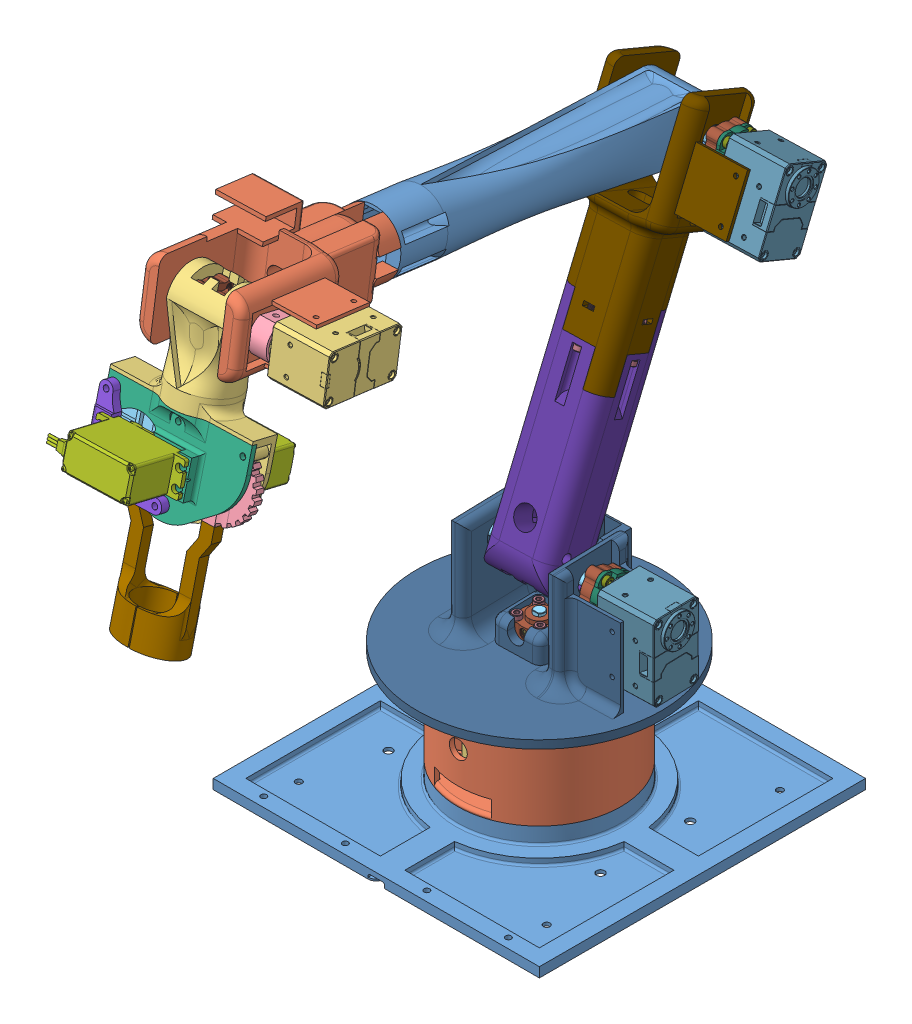
SolidWorks assembly ASSEMBLY_ARM_CHESS_BRAS, configuration Défaut. Lengths in mm.
Overall size (200 394.45 403.36).
100 component instances, 28 part files, 150 mates.
Components (placement in the parent):
- base_robot-1: base_robot [Défaut] at origin size (200 16 200)
- Support_Bearing_V4-1: Support_Bearing_V4 [Défaut] at (0 16 0) x (0 0 1) z (-1 0 0) size (100 58.5 100)
- XL430-W250-1: XL430-W250 [Défaut] at (0 42 0) x (-1 0 0) z (0 1 0) size (28.5 46.5 36.18)
- Coupler_Joint3-1: Coupler_Joint3 [Défaut] at (0 45 0) x (-0.999605 0 0.028091) z (-0.028091 0 -0.999605) size (22.5 11 20.75)
- shaft-1: shaft [2po] at (0 70.4 0) x (0.999605 0 -0.028091) z (0 -1 0) size (6.35 5.71 50.8)
- M3-16mm_91292A115_TYPE 18-8 SS SOCKET HEAD CAP SCREW-1: M3-16mm_91292A115_TYPE 18-8 SS SOCKET HEAD CAP SCREW [91292A115] at (22.5 21 -30) x (0.270289 0 0.962779) z (0 1 0) size (5.5 5.5 19.25)
- M3-16mm_91292A115_TYPE 18-8 SS SOCKET HEAD CAP SCREW-2: M3-16mm_91292A115_TYPE 18-8 SS SOCKET HEAD CAP SCREW [91292A115] at (-22.5 21 30) x (0.142923 0 0.989734) z (0 1 0) size (5.5 5.5 19.25)
- M3-16mm_91292A115_TYPE 18-8 SS SOCKET HEAD CAP SCREW-3: M3-16mm_91292A115_TYPE 18-8 SS SOCKET HEAD CAP SCREW [91292A115] at (-22.5 21 -30) x (-0.967146 0 0.254223) z (0 1 0) size (5.5 5.5 19.25)
- M3-16mm_91292A115_TYPE 18-8 SS SOCKET HEAD CAP SCREW-4: M3-16mm_91292A115_TYPE 18-8 SS SOCKET HEAD CAP SCREW [91292A115] at (22.5 21 30) x (0.348034 0 0.937482) z (0 1 0) size (5.5 5.5 19.25)
- M3-NUT_90710A030_TYPE 18-8 SS THIN HEX NUT - DIN 439B-1: M3-NUT_90710A030_TYPE 18-8 SS THIN HEX NUT - DIN 439B [90710A030] at (22.5 19.4 -30) x (0.887075 0 -0.461625) z (-0.461625 0 -0.887075) size (5.5 2.19 6.35)
- M3-NUT_90710A030_TYPE 18-8 SS THIN HEX NUT - DIN 439B-2: M3-NUT_90710A030_TYPE 18-8 SS THIN HEX NUT - DIN 439B [90710A030] at (-22.5 19.4 -30) x (0.998436 0 0.055912) z (-0.055912 0 0.998436) size (5.5 2.19 6.35)
- M3-NUT_90710A030_TYPE 18-8 SS THIN HEX NUT - DIN 439B-3: M3-NUT_90710A030_TYPE 18-8 SS THIN HEX NUT - DIN 439B [90710A030] at (-22.5 19.4 30) x (0.076416 0 -0.997076) z (0.997076 0 0.076416) size (5.5 2.19 6.35)
- M3-NUT_90710A030_TYPE 18-8 SS THIN HEX NUT - DIN 439B-4: M3-NUT_90710A030_TYPE 18-8 SS THIN HEX NUT - DIN 439B [90710A030] at (22.5 19.4 30) x (-0.208862 0 0.977945) z (-0.977945 0 -0.208862) size (5.5 2.19 6.35)
- bearing-1: bearing [Default] at (0 58.1597 -32.8363) x (0.994869 0.079004 -0.063204) z (0 0.624695 0.780869) size (22.23 22.23 8.73)
- bearing-2: bearing [Default] at (-28.437 58.1597 16.4181) x (0.188165 0.365941 0.911417) z (-0.676252 -0.624695 0.390434) size (22.23 22.23 8.73)
- bearing-3: bearing [Default] at (28.437 58.1597 16.4181) x (0.671098 0.303827 -0.676252) z (0.676252 -0.624695 0.390434) size (22.23 22.23 8.73)
- M2-4mm_TYPE 18-8 SS SOCKET HEAD CAP SCREW-1: M2-4mm_TYPE 18-8 SS SOCKET HEAD CAP SCREW [91292A832] at (-0.2247 43.7 -7.9968) x (0.453166 0 -0.891426) z (0 -1 0) size (3.8 3.8 6.09)
- M2-4mm_TYPE 18-8 SS SOCKET HEAD CAP SCREW-2: M2-4mm_TYPE 18-8 SS SOCKET HEAD CAP SCREW [91292A832] at (-7.9968 43.7 0.2247) x (0.453166 0 -0.891426) z (0 -1 0) size (3.8 3.8 6.09)
- M2-4mm_TYPE 18-8 SS SOCKET HEAD CAP SCREW-3: M2-4mm_TYPE 18-8 SS SOCKET HEAD CAP SCREW [91292A832] at (7.9968 43.7 -0.2247) x (0.453166 0 -0.891426) z (0 -1 0) size (3.8 3.8 6.09)
- base_350W-1: base_350W [Défaut] at (-0.0002 69.5 -0.0002) x (-0.999605 0 0.028091) z (-0.028091 0 -0.999605) size (150 75 150)
- 545548_hub-1: 545548_hub [Default] at (-39.1478 106.1015 -7.8743) x (-0.999605 0 0.028091) z (0.028091 0 0.999605) size (20.57 9.53 20.57)
  - 545548 assembly.STEP-1: 545548 assembly.STEP [Default] at origin size (20.57 9.53 20.57)
    - 545548.STEP-1: 545548.STEP [Default] at (-38.9112 12.0765 8.9709) size (20.57 9.53 20.57)
    - 632138_91375A438.STEP-1: 632138_91375A438.STEP [Default] at (-38.9112 18.109 15.0823) x (0.93363 0.358238 0) z (0 0 1) size (4.83 4.83 6.36)
- M3-20mm_91292A123_TYPE 18-8 SS SOCKET HEAD CAP SCREW-1: M3-20mm_91292A123_TYPE 18-8 SS SOCKET HEAD CAP SCREW [91292A123] at (-6.7178 66.485 7.1063) x (1 0 0) z (0 -1 0) size (5.5 5.5 28.3)
- M3-20mm_91292A123_TYPE 18-8 SS SOCKET HEAD CAP SCREW-2: M3-20mm_91292A123_TYPE 18-8 SS SOCKET HEAD CAP SCREW [91292A123] at (7.1063 66.485 6.7178) x (0.837169 0 0.546944) z (0 -1 0) size (5.5 5.5 28.3)
- M3-20mm_91292A123_TYPE 18-8 SS SOCKET HEAD CAP SCREW-3: M3-20mm_91292A123_TYPE 18-8 SS SOCKET HEAD CAP SCREW [91292A123] at (-7.1063 66.485 -6.7178) x (0.839089 0 0.543994) z (0 -1 0) size (5.5 5.5 28.3)
- M3-20mm_91292A123_TYPE 18-8 SS SOCKET HEAD CAP SCREW-4: M3-20mm_91292A123_TYPE 18-8 SS SOCKET HEAD CAP SCREW [91292A123] at (6.7178 66.485 -7.1063) x (0.837169 0 0.546944) z (0 -1 0) size (5.5 5.5 28.3)
- M3-NUT_90710A030_TYPE 18-8 SS THIN HEX NUT - DIN 439B-5: M3-NUT_90710A030_TYPE 18-8 SS THIN HEX NUT - DIN 439B [90710A030] at (6.7178 73.6 -7.1063) x (-0.877485 0 0.479605) z (0.479605 0 0.877485) size (5.5 2.19 6.35)
- M3-NUT_90710A030_TYPE 18-8 SS THIN HEX NUT - DIN 439B-6: M3-NUT_90710A030_TYPE 18-8 SS THIN HEX NUT - DIN 439B [90710A030] at (-7.1063 73.6 -6.7178) x (0.422721 0 0.90626) z (0.90626 0 -0.422721) size (5.5 2.19 6.35)
- M3-NUT_90710A030_TYPE 18-8 SS THIN HEX NUT - DIN 439B-7: M3-NUT_90710A030_TYPE 18-8 SS THIN HEX NUT - DIN 439B [90710A030] at (-6.7178 73.6 7.1063) x (0.887517 0 0.460775) z (0.460775 0 -0.887517) size (5.5 2.19 6.35)
- M3-NUT_90710A030_TYPE 18-8 SS THIN HEX NUT - DIN 439B-8: M3-NUT_90710A030_TYPE 18-8 SS THIN HEX NUT - DIN 439B [90710A030] at (7.1063 73.6 6.7178) x (0.999903 0 0.013926) z (0.013926 0 -0.999903) size (5.5 2.19 6.35)
- XM430-W350-1: XM430-W350 [Default] at (64.9812 125 -1.5762) x (0.028091 0 0.999605) z (-0.999605 0 0.028091) size (28.5 46.5 42.4)
- coupleur350W-1: coupleur350W [Défaut] at (42.9898 125 -0.9582) x (-0.025922 -0.385253 -0.922447) z (-0.010822 0.922811 -0.385101) size (22.5 5 22.5)
- 545548_hub-2: 545548_hub [Default] at (18.2948 117.7261 -39.5435) x (-0.025765 -0.398399 -0.91685) z (0.011191 -0.917212 0.398242) size (20.57 9.53 20.57)
  - 545548 assembly.STEP-1: 545548 assembly.STEP [Default] at origin size (20.57 9.53 20.57)
    - 545548.STEP-1: 545548.STEP [Default] at (-38.9112 12.0765 8.9709) size (20.57 9.53 20.57)
    - 632138_91375A438.STEP-1: 632138_91375A438.STEP [Default] at (-38.9112 18.109 15.0823) x (0.93363 0.358238 0) z (0 0 1) size (4.83 4.83 6.36)
- M3-8mm_91292A112_TYPE 18-8 SS SOCKET HEAD CAP SCREW-1: M3-8mm_91292A112_TYPE 18-8 SS SOCKET HEAD CAP SCREW [91292A112] at (34.8885 115.9482 -4.4519) x (0.026773 -0.302684 0.952715) z (-0.999605 0 0.028091) size (5.5 5.5 11.2)
- M3-8mm_91292A112_TYPE 18-8 SS SOCKET HEAD CAP SCREW-2: M3-8mm_91292A112_TYPE 18-8 SS SOCKET HEAD CAP SCREW [91292A112] at (35.2473 121.2801 8.3148) x (0.02653 -0.328692 0.944065) z (-0.999605 0 0.028091) size (5.5 5.5 11.2)
- M3-8mm_91292A112_TYPE 18-8 SS SOCKET HEAD CAP SCREW-3: M3-8mm_91292A112_TYPE 18-8 SS SOCKET HEAD CAP SCREW [91292A112] at (34.7387 128.7199 -9.7817) x (0.027877 0.123058 0.992008) z (-0.999605 0 0.028091) size (5.5 5.5 11.2)
- M3-8mm_91292A112_TYPE 18-8 SS SOCKET HEAD CAP SCREW-4: M3-8mm_91292A112_TYPE 18-8 SS SOCKET HEAD CAP SCREW [91292A112] at (35.0975 134.0518 2.985) x (0.026768 -0.303288 0.952523) z (-0.999605 0 0.028091) size (5.5 5.5 11.2)
- shaft-2: shaft [3po] at (3.5054 125 0.1514) x (-0.025765 -0.398399 -0.91685) z (-0.999605 0 0.028091) size (6.35 5.71 76.2)
- 545548_hub-3: 545548_hub [Default] at (-12.9324 117.726 -38.6657) x (-0.025765 -0.398399 -0.91685) z (0.011191 -0.917212 0.398242) size (20.57 9.53 20.57)
  - 545548 assembly.STEP-1: 545548 assembly.STEP [Default] at origin size (20.57 9.53 20.57)
    - 545548.STEP-1: 545548.STEP [Default] at (-38.9112 12.0765 8.9709) size (20.57 9.53 20.57)
    - 632138_91375A438.STEP-1: 632138_91375A438.STEP [Default] at (-38.9112 18.109 15.0823) x (0.93363 0.358238 0) z (0 0 1) size (4.83 4.83 6.36)
- 545548_hub-4: 545548_hub [Default] at (13.216 148.7303 32.0072) x (0.025765 0.398399 0.91685) z (0.011191 -0.917212 0.398242) size (20.57 9.53 20.57)
  - 545548 assembly.STEP-1: 545548 assembly.STEP [Default] at origin size (20.57 9.53 20.57)
    - 545548.STEP-1: 545548.STEP [Default] at (-38.9112 12.0765 8.9709) size (20.57 9.53 20.57)
    - 632138_91375A438.STEP-1: 632138_91375A438.STEP [Default] at (-38.9112 18.109 15.0823) x (0.93363 0.358238 0) z (0 0 1) size (4.83 4.83 6.36)
- inferior_segment_1-1: inferior_segment_1 [Défaut] at (-0.023 128.302 -1.1843) x (-0.999605 0 0.028091) z (-0.025765 -0.398399 -0.91685) size (42.86 137.5 35)
- superior350W-1: superior350W [Défaut] at (-0.9183 201.6789 -33.0436) x (-0.999605 0 0.028091) z (-0.025765 -0.398399 -0.91685) size (90 145.3 45)
- M3-20mm_91292A123_TYPE 18-8 SS SOCKET HEAD CAP SCREW-5: M3-20mm_91292A123_TYPE 18-8 SS SOCKET HEAD CAP SCREW [91292A123] at (16.4046 240.2018 -50.2698) x (-0.885368 -0.194198 -0.422386) z (-0.011191 0.917212 -0.398242) size (5.5 5.5 28.3)
- M3-20mm_91292A123_TYPE 18-8 SS SOCKET HEAD CAP SCREW-6: M3-20mm_91292A123_TYPE 18-8 SS SOCKET HEAD CAP SCREW [91292A123] at (-0.9941 246.2973 -35.742) x (0.744767 0.273398 0.608749) z (-0.011191 0.917212 -0.398242) size (5.5 5.5 28.3)
- M3-20mm_91292A123_TYPE 18-8 SS SOCKET HEAD CAP SCREW-7: M3-20mm_91292A123_TYPE 18-8 SS SOCKET HEAD CAP SCREW [91292A123] at (-1.7826 234.1063 -63.7976) x (-0.892653 -0.188637 -0.409374) z (-0.011191 0.917212 -0.398242) size (5.5 5.5 28.3)
- M3-20mm_91292A123_TYPE 18-8 SS SOCKET HEAD CAP SCREW-8: M3-20mm_91292A123_TYPE 18-8 SS SOCKET HEAD CAP SCREW [91292A123] at (-19.1813 240.2018 -49.2698) x (0.944545 0.140413 0.296849) z (-0.011191 0.917212 -0.398242) size (5.5 5.5 28.3)
- XM430-W350-2: XM430-W350 [Default] at (58.6707 315.9714 -84.1091) x (0.025765 0.398399 0.91685) z (-0.999605 0 0.028091) size (28.5 46.5 42.4)
- coupleur350W-2: coupleur350W [Défaut] at (36.6794 315.9714 -83.4911) x (0.004247 -0.988504 0.151137) z (-0.027768 -0.151196 -0.988114) size (22.5 5 22.5)
- M3-8mm_91292A112_TYPE 18-8 SS SOCKET HEAD CAP SCREW-5: M3-8mm_91292A112_TYPE 18-8 SS SOCKET HEAD CAP SCREW [91292A112] at (28.5198 308.0847 -89.0583) x (0.012773 -0.890647 0.454517) z (-0.999605 0 0.028091) size (5.5 5.5 11.2)
- M3-8mm_91292A112_TYPE 18-8 SS SOCKET HEAD CAP SCREW-6: M3-8mm_91292A112_TYPE 18-8 SS SOCKET HEAD CAP SCREW [91292A112] at (28.8453 323.8582 -77.4745) x (0.012773 -0.890647 0.454517) z (-0.999605 0 0.028091) size (5.5 5.5 11.2)
- M3-8mm_91292A112_TYPE 18-8 SS SOCKET HEAD CAP SCREW-7: M3-8mm_91292A112_TYPE 18-8 SS SOCKET HEAD CAP SCREW [91292A112] at (28.461 321.7656 -91.15) x (0.006713 0.971024 0.238887) z (-0.999605 0 0.028091) size (5.5 5.5 11.2)
- M3-8mm_91292A112_TYPE 18-8 SS SOCKET HEAD CAP SCREW-8: M3-8mm_91292A112_TYPE 18-8 SS SOCKET HEAD CAP SCREW [91292A112] at (28.9041 310.1773 -75.3828) x (0.012773 -0.890647 0.454517) z (-0.999605 0 0.028091) size (5.5 5.5 11.2)
- 545548_hub-5: 545548_hub [Default] at (13.1711 355.7916 -79.8447) x (-0.004247 0.988504 -0.151137) z (-0.027768 -0.151196 -0.988114) size (20.57 9.53 20.57)
  - 545548 assembly.STEP-1: 545548 assembly.STEP [Default] at origin size (20.57 9.53 20.57)
    - 545548.STEP-1: 545548.STEP [Default] at (-38.9112 12.0765 8.9709) size (20.57 9.53 20.57)
    - 632138_91375A438.STEP-1: 632138_91375A438.STEP [Default] at (-38.9112 18.109 15.0823) x (0.93363 0.358238 0) z (0 0 1) size (4.83 4.83 6.36)
- shaft-3: shaft [3po] at (-2.805 315.9714 -82.3815) x (0.004247 -0.988504 0.151137) z (0.999605 0 -0.028091) size (6.35 5.71 76.2)
- segment_2-1: segment_2 [Default] at (-3.5309 315.9714 -82.3611) x (0.999605 0 -0.028091) z (0.027768 0.151196 0.988114) size (38.54 37.14 206.68)
- 545548_hub-6: 545548_hub [Default] at (9.37 278.864 -67.9668) x (0.004247 -0.988504 0.151137) z (-0.027768 -0.151196 -0.988114) size (20.57 9.53 20.57)
  - 545548 assembly.STEP-1: 545548 assembly.STEP [Default] at origin size (20.57 9.53 20.57)
    - 545548.STEP-1: 545548.STEP [Default] at (-38.9112 12.0765 8.9709) size (20.57 9.53 20.57)
    - 632138_91375A438.STEP-1: 632138_91375A438.STEP [Default] at (-38.9112 18.109 15.0823) x (0.93363 0.358238 0) z (0 0 1) size (4.83 4.83 6.36)
- 545548_hub-7: 545548_hub [Default] at (-15.104 355.7916 -79.0502) x (-0.004247 0.988504 -0.151137) z (-0.027768 -0.151196 -0.988114) size (20.57 9.53 20.57)
  - 545548 assembly.STEP-1: 545548 assembly.STEP [Default] at origin size (20.57 9.53 20.57)
    - 545548.STEP-1: 545548.STEP [Default] at (-38.9112 12.0765 8.9709) size (20.57 9.53 20.57)
    - 632138_91375A438.STEP-1: 632138_91375A438.STEP [Default] at (-38.9112 18.109 15.0823) x (0.93363 0.358238 0) z (0 0 1) size (4.83 4.83 6.36)
- wrist-1: wrist [Défaut] at (1.3199 340.3959 77.3092) x (-0.999605 0 0.028091) z (-0.004247 0.988504 -0.151137) size (91 115.8 55)
- XL430-W250-2: XL430-W250 [Défaut] at (42.7631 358.9727 199.2997) x (-0.004247 0.988504 -0.151137) z (-0.999605 0 0.028091) size (28.5 46.5 36.18)
- Coupler_Joint3-2: Coupler_Joint3 [Défaut] at (39.7642 358.9727 199.3839) x (0.027195 0.250474 0.967741) z (0.007036 -0.968123 0.250375) size (22.5 11 20.75)
- shaft-4: shaft [3po] at (1.6793 358.9727 200.4542) x (0.027195 0.250474 0.967741) z (-0.999605 0 0.028091) size (6.35 5.71 76.2)
- 545548_hub-8: 545548_hub [Default] at (15.5705 340.5415 164.626) x (-0.027195 -0.250474 -0.967741) z (-0.007036 0.968123 -0.250375) size (20.57 9.53 20.57)
  - 545548 assembly.STEP-1: 545548 assembly.STEP [Default] at origin size (20.57 9.53 20.57)
    - 545548.STEP-1: 545548.STEP [Default] at (-38.9112 12.0765 8.9709) size (20.57 9.53 20.57)
    - 632138_91375A438.STEP-1: 632138_91375A438.STEP [Default] at (-38.9112 18.109 15.0823) x (0.93363 0.358238 0) z (0 0 1) size (4.83 4.83 6.36)
- 545548_hub-9: 545548_hub [Default] at (-6.4565 360.0339 240.6164) x (0.027195 0.250474 0.967741) z (-0.007036 0.968123 -0.250375) size (20.57 9.53 20.57)
  - 545548 assembly.STEP-1: 545548 assembly.STEP [Default] at origin size (20.57 9.53 20.57)
    - 545548.STEP-1: 545548.STEP [Default] at (-38.9112 12.0765 8.9709) size (20.57 9.53 20.57)
    - 632138_91375A438.STEP-1: 632138_91375A438.STEP [Default] at (-38.9112 18.109 15.0823) x (0.93363 0.358238 0) z (0 0 1) size (4.83 4.83 6.36)
- pince-2: pince [Défaut] at (4.0791 358.9727 200.3868) x (0.999605 0 -0.028091) z (0.007036 -0.968123 0.250375) size (89.66 95.98 180.03)
  - minisegmentServo-1: minisegmentServo [Default] at origin size (85 38 118.68)
  - gearnoMot - Copie-2: gearnoMot - Copie [Défaut] at (21.5 5 72.8) x (-0.990981 0 -0.134004) z (-0.134004 0 0.990981) size (43.87 6.5 43.87)
  - gearMot-1: gearMot [Défaut] at (-21.5 0 72.8) x (0.999997 0 0.002496) z (-0.002496 0 0.999997) size (43.87 7.5 43.44)
  - toppince-1: toppince [Défaut] at (-0.0037 10 45.8) size (85 14.77 55)
  - hs-422_sws-1: hs-422_sws [Default] at (-11.213 28.2654 82.706) x (0 0 -1) z (-1 0 0) size (19.81 42.14 58.23)
  - supportServo-1: supportServo [Défaut] at (-38.5037 13 52.8) size (46.5 6.78 48)
  - bout_pince-1: bout_pince [Défaut] at (21.4995 5 72.7083) x (-0.990981 0 -0.134004) z (-0.134004 0 0.990981) size (22.79 28.4 74.62)
  - bout_pince-2: bout_pince [Défaut] at (-21.4997 1.5 72.6719) x (0.990612 0 -0.136701) z (0.136701 0 0.990612) size (22.79 28.4 74.62)
  - BOTSUPP-1: BOTSUPP [Défaut] at (0 -3 72.8) x (-1 0 0) z (0 0 1) size (52.83 14.74 50)
  - hs-422_sws-2: hs-422_sws [Default] at (0.128 -26.2245 67.798) x (0 0 1) z (-1 0 0) size (19.81 42.14 58.23)
Mates (geometry in assembly coordinates):
- Coaxiale1: concentric anti-aligned: circle of base_robot-1; circle of Support_Bearing_V4-1
- Coaxiale2: concentric anti-aligned: circle of base_robot-1; circle of Support_Bearing_V4-1
- Coïncidente1: coincident anti-aligned: plane of base_robot-1 through (0 16 0) normal (0 1 0); plane of Support_Bearing_V4-1 through (0 16 0) normal (0 -1 0)
- Coaxiale3: concentric anti-aligned: circle of base_robot-1; circle of XL430-W250-1
- Coaxiale4: concentric anti-aligned: circle of base_robot-1; circle of XL430-W250-1
- Coïncidente2: coincident anti-aligned: plane of base_robot-1 through (0 6 0) normal (0 1 0); plane of XL430-W250-1 through (0 6 0) normal (0 -1 0)
- Coïncidente3: coincident anti-aligned: plane of XL430-W250-1 through (0 42 0) normal (0 1 0); plane of Coupler_Joint3-1 through (0 42 0) normal (0 -1 0)
- Coaxiale7: concentric anti-aligned: circle of XL430-W250-1; circle of Coupler_Joint3-1
- Coaxiale8: concentric anti-aligned: circle of Coupler_Joint3-1; circle of shaft-1
- Parallèle1: parallel anti-aligned: plane of Coupler_Joint3-1 through (-3.1173 53 2.9887) normal (-0.028091 0 -0.999605); plane of shaft-1 through (1.9756 45 2.4855) normal (0.028091 0 0.999605)
- Coïncidente4: coincident anti-aligned: plane of Coupler_Joint3-1 through (0 45 0) normal (0 1 0); plane of shaft-1 through (0 45 0) normal (0 -1 0)
- Coaxiale9: concentric aligned: circle of Support_Bearing_V4-1; circle of M3-16mm_91292A115_TYPE 18-8 SS SOCKET HEAD CAP SCREW-1
- Coïncidente5: coincident anti-aligned: plane of base_robot-1 through (24.75 5 -30) normal (0 -1 0); plane of M3-16mm_91292A115_TYPE 18-8 SS SOCKET HEAD CAP SCREW-1 through (22.5 5 -30) normal (0 1 0)
- Coaxiale10: concentric aligned: circle of base_robot-1; circle of M3-16mm_91292A115_TYPE 18-8 SS SOCKET HEAD CAP SCREW-4
- Coaxiale11: concentric aligned: circle of base_robot-1; circle of M3-16mm_91292A115_TYPE 18-8 SS SOCKET HEAD CAP SCREW-3
- Coaxiale12: concentric anti-aligned: circle of base_robot-1; circle of M3-16mm_91292A115_TYPE 18-8 SS SOCKET HEAD CAP SCREW-2
- Coïncidente6: coincident anti-aligned: plane of base_robot-1 through (-20.25 5 30) normal (0 -1 0); plane of M3-16mm_91292A115_TYPE 18-8 SS SOCKET HEAD CAP SCREW-2 through (-22.5 5 30) normal (0 1 0)
- Coïncidente7: coincident anti-aligned: plane of base_robot-1 through (24.75 5 30) normal (0 -1 0); circle of M3-16mm_91292A115_TYPE 18-8 SS SOCKET HEAD CAP SCREW-4
- Coïncidente8: coincident anti-aligned: plane of base_robot-1 through (-20.25 5 -30) normal (0 -1 0); plane of M3-16mm_91292A115_TYPE 18-8 SS SOCKET HEAD CAP SCREW-3 through (-22.5 5 -30) normal (0 1 0)
- Coaxiale13: concentric anti-aligned: circle of M3-16mm_91292A115_TYPE 18-8 SS SOCKET HEAD CAP SCREW-1; circle of M3-NUT_90710A030_TYPE 18-8 SS THIN HEX NUT - DIN 439B-1
- Coaxiale14: concentric aligned: circle of M3-16mm_91292A115_TYPE 18-8 SS SOCKET HEAD CAP SCREW-3; circle of M3-NUT_90710A030_TYPE 18-8 SS THIN HEX NUT - DIN 439B-2
- Coaxiale15: concentric aligned: circle of M3-16mm_91292A115_TYPE 18-8 SS SOCKET HEAD CAP SCREW-2; circle of M3-NUT_90710A030_TYPE 18-8 SS THIN HEX NUT - DIN 439B-3
- Coaxiale16: concentric aligned: circle of M3-16mm_91292A115_TYPE 18-8 SS SOCKET HEAD CAP SCREW-4; circle of M3-NUT_90710A030_TYPE 18-8 SS THIN HEX NUT - DIN 439B-4
- Coïncidente9: coincident anti-aligned: plane of Support_Bearing_V4-1 through (0 18.5 0) normal (0 1 0); plane of M3-NUT_90710A030_TYPE 18-8 SS THIN HEX NUT - DIN 439B-4 through (24.6271 18.5 27.6423) normal (0 -1 0)
- Coïncidente10: coincident anti-aligned: plane of Support_Bearing_V4-1 through (0 18.5 0) normal (0 1 0); plane of M3-NUT_90710A030_TYPE 18-8 SS THIN HEX NUT - DIN 439B-3 through (-24.2932 18.5 32.6206) normal (0 -1 0)
- Coïncidente11: coincident anti-aligned: plane of Support_Bearing_V4-1 through (0 18.5 0) normal (0 1 0); plane of M3-NUT_90710A030_TYPE 18-8 SS THIN HEX NUT - DIN 439B-2 through (-25.1569 18.5 -31.739) normal (0 -1 0)
- Coïncidente12: coincident anti-aligned: plane of Support_Bearing_V4-1 through (0 18.5 0) normal (0 1 0); plane of M3-NUT_90710A030_TYPE 18-8 SS THIN HEX NUT - DIN 439B-1 through (20.7935 18.5 -27.3221) normal (0 -1 0)
- Coaxiale17: concentric anti-aligned: circle of Support_Bearing_V4-1; circle of bearing-3
- Coaxiale18: concentric anti-aligned: circle of Support_Bearing_V4-1; circle of bearing-2
- Coaxiale19: concentric aligned: circle of Support_Bearing_V4-1; circle of bearing-1
- Coïncidente13: coincident anti-aligned: plane of Support_Bearing_V4-1 through (44.2612 69.5 18.3373) normal (-0.676252 0.624695 -0.390434); plane of bearing-3 through (31.3897 55.4322 18.1229) normal (0.676252 -0.624695 0.390434)
- Coïncidente14: coincident anti-aligned: plane of Support_Bearing_V4-1 through (-6.25 69.5 -47.5) normal (0 0.624695 0.780869); plane of bearing-1 through (0 55.4322 -36.2457) normal (0 -0.624695 -0.780869)
- Coïncidente15: coincident anti-aligned: plane of Support_Bearing_V4-1 through (-38.0112 69.5 29.1627) normal (0.676252 0.624695 -0.390434); plane of bearing-2 through (-31.3897 55.4322 18.1229) normal (-0.676252 -0.624695 0.390434)
- Coaxiale20: concentric aligned: circle of Coupler_Joint3-1; circle of M2-4mm_TYPE 18-8 SS SOCKET HEAD CAP SCREW-1
- Coïncidente16: coincident anti-aligned: plane of Coupler_Joint3-1 through (-1.4742 47.7 -7.9617) normal (0 1 0); plane of M2-4mm_TYPE 18-8 SS SOCKET HEAD CAP SCREW-1 through (-0.2247 47.7 -7.9968) normal (0 -1 0)
- Coaxiale21: concentric anti-aligned: circle of Coupler_Joint3-1; circle of M2-4mm_TYPE 18-8 SS SOCKET HEAD CAP SCREW-3
- Coaxiale22: concentric aligned: circle of Coupler_Joint3-1; circle of M2-4mm_TYPE 18-8 SS SOCKET HEAD CAP SCREW-2
- Coïncidente17: coincident anti-aligned: plane of Coupler_Joint3-1 through (6.7473 47.7 -0.1896) normal (0 1 0); plane of M2-4mm_TYPE 18-8 SS SOCKET HEAD CAP SCREW-3 through (7.9968 47.7 -0.2247) normal (0 -1 0)
- Coïncidente18: coincident anti-aligned: plane of Coupler_Joint3-1 through (-9.2463 47.7 0.2598) normal (0 1 0); plane of M2-4mm_TYPE 18-8 SS SOCKET HEAD CAP SCREW-2 through (-7.9968 47.7 0.2247) normal (0 -1 0)
- Coaxiale23: concentric anti-aligned: circle of Support_Bearing_V4-1; circle of base_350W-1
- Coaxiale27: concentric anti-aligned: circle of base_350W-1; circle of 545548_hub-1/545548 assembly.STEP-1/545548.STEP-1
- Coaxiale28: concentric anti-aligned: circle of base_350W-1; circle of 545548_hub-1/545548 assembly.STEP-1/545548.STEP-1
- Coïncidente20: coincident anti-aligned: plane of base_350W-1 through (7.1063 84.5 6.7178) normal (0 1 0); plane of 545548_hub-1/545548 assembly.STEP-1/545548.STEP-1 through (3.3589 84.5 -3.5532) normal (0 -1 0)
- Coaxiale29: concentric anti-aligned: circle of 545548_hub-1/545548 assembly.STEP-1/545548.STEP-1; circle of M3-20mm_91292A123_TYPE 18-8 SS SOCKET HEAD CAP SCREW-1
- Coïncidente21: coincident anti-aligned: plane of 545548_hub-1/545548 assembly.STEP-1/545548.STEP-1 through (3.3589 91.485 -3.5532) normal (0 1 0); plane of M3-20mm_91292A123_TYPE 18-8 SS SOCKET HEAD CAP SCREW-1 through (-6.7178 91.485 7.1063) normal (0 -1 0)
- Coaxiale30: concentric anti-aligned: circle of 545548_hub-1/545548 assembly.STEP-1/545548.STEP-1; circle of M3-20mm_91292A123_TYPE 18-8 SS SOCKET HEAD CAP SCREW-2
- Coaxiale31: concentric anti-aligned: circle of 545548_hub-1/545548 assembly.STEP-1/545548.STEP-1; circle of M3-20mm_91292A123_TYPE 18-8 SS SOCKET HEAD CAP SCREW-3
- Coaxiale32: concentric anti-aligned: circle of 545548_hub-1/545548 assembly.STEP-1/545548.STEP-1; circle of M3-20mm_91292A123_TYPE 18-8 SS SOCKET HEAD CAP SCREW-4
- Coïncidente22: coincident anti-aligned: plane of 545548_hub-1/545548 assembly.STEP-1/545548.STEP-1 through (3.3589 91.485 -3.5532) normal (0 1 0); plane of M3-20mm_91292A123_TYPE 18-8 SS SOCKET HEAD CAP SCREW-3 through (-7.1063 91.485 -6.7178) normal (0 -1 0)
- Coïncidente23: coincident anti-aligned: plane of 545548_hub-1/545548 assembly.STEP-1/545548.STEP-1 through (3.3589 91.485 -3.5532) normal (0 1 0); plane of M3-20mm_91292A123_TYPE 18-8 SS SOCKET HEAD CAP SCREW-2 through (7.1063 91.485 6.7178) normal (0 -1 0)
- Coïncidente24: coincident anti-aligned: plane of 545548_hub-1/545548 assembly.STEP-1/545548.STEP-1 through (3.3589 91.485 -3.5532) normal (0 1 0); circle of M3-20mm_91292A123_TYPE 18-8 SS SOCKET HEAD CAP SCREW-4
- Coaxiale33: concentric anti-aligned: unknown of shaft-1; unknown of 545548_hub-1/545548 assembly.STEP-1/545548.STEP-1
- Parallèle2: parallel aligned: plane of shaft-1 through (1.9756 45 2.4855) normal (0.028091 0 0.999605); plane of base_350W-1 through (15.4152 94.5 14.5725) normal (0.028091 0 0.999605)
- Coaxiale34: concentric aligned: circle of M3-20mm_91292A123_TYPE 18-8 SS SOCKET HEAD CAP SCREW-4; circle of M3-NUT_90710A030_TYPE 18-8 SS THIN HEX NUT - DIN 439B-5
- Coïncidente25: coincident anti-aligned: plane of base_350W-1 through (5.3434 74.5 -7.0681) normal (0 -1 0); plane of M3-NUT_90710A030_TYPE 18-8 SS THIN HEX NUT - DIN 439B-5 through (8.3694 74.5 -9.8184) normal (0 1 0)
- Coaxiale35: concentric aligned: circle of M3-20mm_91292A123_TYPE 18-8 SS SOCKET HEAD CAP SCREW-3; circle of M3-NUT_90710A030_TYPE 18-8 SS THIN HEX NUT - DIN 439B-6
- Coaxiale36: concentric aligned: circle of M3-20mm_91292A123_TYPE 18-8 SS SOCKET HEAD CAP SCREW-1; circle of M3-NUT_90710A030_TYPE 18-8 SS THIN HEX NUT - DIN 439B-7
- Coaxiale37: concentric aligned: circle of M3-20mm_91292A123_TYPE 18-8 SS SOCKET HEAD CAP SCREW-2; circle of M3-NUT_90710A030_TYPE 18-8 SS THIN HEX NUT - DIN 439B-8
- Coïncidente26: coincident anti-aligned: plane of base_350W-1 through (-8.4812 74.5 -6.6796) normal (0 -1 0); plane of M3-NUT_90710A030_TYPE 18-8 SS THIN HEX NUT - DIN 439B-6 through (-9.7077 74.5 -8.5389) normal (0 1 0)
- Coïncidente27: coincident anti-aligned: plane of base_350W-1 through (5.7319 74.5 6.7565) normal (0 -1 0); plane of M3-NUT_90710A030_TYPE 18-8 SS THIN HEX NUT - DIN 439B-8 through (4.3345 74.5 8.2671) normal (0 1 0)
- Coïncidente28: coincident anti-aligned: plane of base_350W-1 through (-8.0927 74.5 7.1449) normal (0 -1 0); plane of M3-NUT_90710A030_TYPE 18-8 SS THIN HEX NUT - DIN 439B-7 through (-9.8901 74.5 7.2483) normal (0 1 0)
- Coïncidente29: coincident anti-aligned: plane of Support_Bearing_V4-1 through (0 74.5 0) normal (0 1 0); plane of base_350W-1 through (-0.0002 74.5 -0.0002) normal (0 -1 0)
- Coaxiale38: concentric anti-aligned: circle of XM430-W350-1; circle of coupleur350W-1
- Coïncidente30: coincident anti-aligned: plane of XM430-W350-1 through (45.9887 125 -1.0425) normal (-0.999605 0 0.028091); plane of coupleur350W-1 through (45.9887 125 -1.0425) normal (0.999605 0 -0.028091)
- Coaxiale41: concentric anti-aligned: circle of coupleur350W-1; circle of 545548_hub-2/545548 assembly.STEP-1/545548.STEP-1
- Coïncidente31: coincident anti-aligned: plane of coupleur350W-1 through (40.9906 125 -0.902) normal (-0.999605 0 0.028091); plane of 545548_hub-2/545548 assembly.STEP-1/545548.STEP-1 through (41.041 129.5486 0.891) normal (0.999605 0 -0.028091)
- Coaxiale44: concentric aligned: circle of base_350W-1; circle of XM430-W350-1
- Coaxiale45: concentric anti-aligned: circle of coupleur350W-1; circle of M3-8mm_91292A112_TYPE 18-8 SS SOCKET HEAD CAP SCREW-4
- Coaxiale46: concentric anti-aligned: circle of coupleur350W-1; circle of M3-8mm_91292A112_TYPE 18-8 SS SOCKET HEAD CAP SCREW-2
- Coaxiale47: concentric anti-aligned: circle of coupleur350W-1; circle of M3-8mm_91292A112_TYPE 18-8 SS SOCKET HEAD CAP SCREW-1
- Coaxiale48: concentric anti-aligned: circle of coupleur350W-1; circle of M3-8mm_91292A112_TYPE 18-8 SS SOCKET HEAD CAP SCREW-3
- Coïncidente32: coincident anti-aligned: plane of coupleur350W-1 through (42.9898 125 -0.9582) normal (0.999605 0 -0.028091); plane of M3-8mm_91292A112_TYPE 18-8 SS SOCKET HEAD CAP SCREW-4 through (43.0943 134.0518 2.7602) normal (-0.999605 0 0.028091)
- Coïncidente34: coincident anti-aligned: plane of coupleur350W-1 through (42.9898 125 -0.9582) normal (0.999605 0 -0.028091); plane of M3-8mm_91292A112_TYPE 18-8 SS SOCKET HEAD CAP SCREW-3 through (42.7356 128.7199 -10.0064) normal (-0.999605 0 0.028091)
- Coïncidente35: coincident anti-aligned: plane of coupleur350W-1 through (42.9898 125 -0.9582) normal (0.999605 0 -0.028091); plane of M3-8mm_91292A112_TYPE 18-8 SS SOCKET HEAD CAP SCREW-2 through (43.2441 121.2801 8.09) normal (-0.999605 0 0.028091)
- Coïncidente36: coincident anti-aligned: plane of coupleur350W-1 through (42.9898 125 -0.9582) normal (0.999605 0 -0.028091); plane of M3-8mm_91292A112_TYPE 18-8 SS SOCKET HEAD CAP SCREW-1 through (42.8854 115.9482 -4.6766) normal (-0.999605 0 0.028091)
- Coaxiale49: concentric aligned: unknown of 545548_hub-2/545548 assembly.STEP-1/545548.STEP-1; unknown of shaft-2
- Parallèle3: parallel aligned: plane of 545548_hub-2/545548 assembly.STEP-1/632138_91375A438.STEP-1 through (37.599 116.8468 2.7361) normal (0.011191 -0.917212 0.398242); plane of shaft-2 through (-34.6002 121.9113 0.4866) normal (0.011191 -0.917212 0.398242)
- Coïncidente38: coincident anti-aligned: plane of XM430-W350-1 through (41.5904 125 -0.9189) normal (-0.999605 0 0.028091); plane of shaft-2 through (41.5904 125 -0.9189) normal (0.999605 0 -0.028091)
- Parallèle4: parallel aligned: plane of 545548_hub-2/545548 assembly.STEP-1/545548.STEP-1 through (34.0588 129.5486 1.0872) normal (-0.999605 0 0.028091); plane of M3-8mm_91292A112_TYPE 18-8 SS SOCKET HEAD CAP SCREW-1 through (34.8885 115.9482 -4.4519) normal (-0.999605 0 0.028091)
- Coaxiale50: concentric aligned: circle of base_350W-1; circle of XM430-W350-1
- Coïncidente40: coincident anti-aligned: plane of base_350W-1 through (29.6456 137.5 13.6724) normal (-0.028091 0 -0.999605); plane of XM430-W350-1 through (82.3747 89.75 12.1906) normal (0.028091 0 0.999605)
- Coaxiale51: concentric anti-aligned: circle of 545548_hub-3/545548 assembly.STEP-1/545548.STEP-1; circle of 545548_hub-4/545548 assembly.STEP-1/545548.STEP-1
- Coaxiale52: concentric anti-aligned: circle of 545548_hub-3/545548 assembly.STEP-1/545548.STEP-1; circle of 545548_hub-4/545548 assembly.STEP-1/545548.STEP-1
- Coïncidente41: coincident anti-aligned: plane of 545548_hub-3/545548 assembly.STEP-1/545548.STEP-1 through (0.2422 124.9999 0.2434) normal (-0.999605 0 0.028091); plane of 545548_hub-4/545548 assembly.STEP-1/545548.STEP-1 through (0.2422 124.9999 0.2434) normal (0.999605 0 -0.028091)
- Coaxiale53: concentric anti-aligned: circle of 545548_hub-3/545548 assembly.STEP-1/545548.STEP-1; circle of inferior_segment_1-1
- Coaxiale54: concentric anti-aligned: circle of 545548_hub-3/545548 assembly.STEP-1/545548.STEP-1; circle of inferior_segment_1-1
- Coïncidente42: coincident anti-aligned: plane of 545548_hub-3/545548 assembly.STEP-1/545548.STEP-1 through (9.8138 129.5485 1.7688) normal (0.999605 0 -0.028091); plane of inferior_segment_1-1 through (9.3752 130.3359 -13.839) normal (-0.999605 0 0.028091)
- Coaxiale55: concentric anti-aligned: circle of shaft-2; circle of inferior_segment_1-1
- Distance1: distance = 3.9895 mm anti-aligned: plane of inferior_segment_1-1 through (18.1753 231.3954 -65.58) normal (0.999605 0 -0.028091); plane of base_350W-1 through (26.0971 139.5 74.296) normal (-0.999605 0 0.028091)
- Parallèle5: parallel anti-aligned: plane of shaft-2 through (-34.6002 121.9113 0.4866) normal (0.011191 -0.917212 0.398242); plane of inferior_segment_1-1 through (-1.1421 220.0232 -41.0085) normal (-0.011191 0.917212 -0.398242)
- Verrouiller1: lock: 
- Coaxiale56: concentric anti-aligned: circle of inferior_segment_1-1; circle of superior350W-1
- Coaxiale57: concentric anti-aligned: circle of inferior_segment_1-1; circle of superior350W-1
- Coïncidente43: coincident anti-aligned: plane of inferior_segment_1-1 through (-0.9183 201.6789 -33.0436) normal (-0.011191 0.917212 -0.398242); plane of superior350W-1 through (-0.9183 201.6789 -33.0436) normal (0.011191 -0.917212 0.398242)
- Coaxiale58: concentric anti-aligned: circle of inferior_segment_1-1; circle of M3-20mm_91292A123_TYPE 18-8 SS SOCKET HEAD CAP SCREW-6
- Coïncidente44: coincident anti-aligned: plane of inferior_segment_1-1 through (-0.7144 223.367 -25.7859) normal (0.011191 -0.917212 0.398242); plane of M3-20mm_91292A123_TYPE 18-8 SS SOCKET HEAD CAP SCREW-6 through (-0.7144 223.367 -25.7859) normal (-0.011191 0.917212 -0.398242)
- Coaxiale59: concentric aligned: circle of inferior_segment_1-1; circle of M3-20mm_91292A123_TYPE 18-8 SS SOCKET HEAD CAP SCREW-5
- Coïncidente45: coincident anti-aligned: plane of inferior_segment_1-1 through (16.6844 217.2715 -40.3138) normal (0.011191 -0.917212 0.398242); plane of M3-20mm_91292A123_TYPE 18-8 SS SOCKET HEAD CAP SCREW-5 through (16.6844 217.2715 -40.3138) normal (-0.011191 0.917212 -0.398242)
- Coaxiale60: concentric aligned: circle of inferior_segment_1-1; circle of M3-20mm_91292A123_TYPE 18-8 SS SOCKET HEAD CAP SCREW-7
- Coïncidente46: coincident anti-aligned: plane of inferior_segment_1-1 through (-1.5028 211.176 -53.8416) normal (0.011191 -0.917212 0.398242); plane of M3-20mm_91292A123_TYPE 18-8 SS SOCKET HEAD CAP SCREW-7 through (-1.5028 211.176 -53.8416) normal (-0.011191 0.917212 -0.398242)
- Coaxiale61: concentric anti-aligned: circle of inferior_segment_1-1; circle of M3-20mm_91292A123_TYPE 18-8 SS SOCKET HEAD CAP SCREW-8
- Coïncidente47: coincident anti-aligned: plane of inferior_segment_1-1 through (-18.9015 217.2715 -39.3137) normal (0.011191 -0.917212 0.398242); plane of M3-20mm_91292A123_TYPE 18-8 SS SOCKET HEAD CAP SCREW-8 through (-18.9015 217.2715 -39.3137) normal (-0.011191 0.917212 -0.398242)
- Coaxiale64: concentric aligned: circle of XM430-W350-2; circle of coupleur350W-2
- Coïncidente48: coincident anti-aligned: plane of XM430-W350-2 through (39.6782 315.9714 -83.5754) normal (-0.999605 0 0.028091); plane of coupleur350W-2 through (39.6782 315.9714 -83.5754) normal (0.999605 0 -0.028091)
- Coaxiale65: concentric anti-aligned: circle of coupleur350W-2; circle of M3-8mm_91292A112_TYPE 18-8 SS SOCKET HEAD CAP SCREW-5
- Coaxiale66: concentric aligned: circle of coupleur350W-2; circle of M3-8mm_91292A112_TYPE 18-8 SS SOCKET HEAD CAP SCREW-7
- Coaxiale67: concentric aligned: circle of coupleur350W-2; circle of M3-8mm_91292A112_TYPE 18-8 SS SOCKET HEAD CAP SCREW-6
- Coaxiale68: concentric aligned: circle of coupleur350W-2; circle of M3-8mm_91292A112_TYPE 18-8 SS SOCKET HEAD CAP SCREW-8
- Coïncidente49: coincident anti-aligned: plane of coupleur350W-2 through (36.6794 315.9714 -83.4911) normal (0.999605 0 -0.028091); plane of M3-8mm_91292A112_TYPE 18-8 SS SOCKET HEAD CAP SCREW-7 through (36.4579 321.7656 -91.3747) normal (-0.999605 0 0.028091)
- Coïncidente50: coincident anti-aligned: plane of coupleur350W-2 through (36.6794 315.9714 -83.4911) normal (0.999605 0 -0.028091); plane of M3-8mm_91292A112_TYPE 18-8 SS SOCKET HEAD CAP SCREW-5 through (36.5167 308.0847 -89.283) normal (-0.999605 0 0.028091)
- Coïncidente51: coincident anti-aligned: plane of coupleur350W-2 through (36.6794 315.9714 -83.4911) normal (0.999605 0 -0.028091); plane of M3-8mm_91292A112_TYPE 18-8 SS SOCKET HEAD CAP SCREW-8 through (36.901 310.1773 -75.6075) normal (-0.999605 0 0.028091)
- Coïncidente52: coincident anti-aligned: plane of coupleur350W-2 through (36.6794 315.9714 -83.4911) normal (0.999605 0 -0.028091); plane of M3-8mm_91292A112_TYPE 18-8 SS SOCKET HEAD CAP SCREW-6 through (36.8422 323.8582 -77.6992) normal (-0.999605 0 0.028091)
- Coaxiale69: concentric anti-aligned: circle of coupleur350W-2; circle of 545548_hub-5/545548 assembly.STEP-1/545548.STEP-1
- Coïncidente54: coincident anti-aligned: plane of coupleur350W-2 through (34.6802 315.9714 -83.4349) normal (-0.999605 0 0.028091); plane of 545548_hub-5/545548 assembly.STEP-1/545548.STEP-1 through (34.7909 313.0765 -79.4961) normal (0.999605 0 -0.028091)
- Coaxiale70: concentric anti-aligned: unknown of 545548_hub-5/545548 assembly.STEP-1/545548.STEP-1; unknown of shaft-3
- Parallèle6: parallel aligned: plane of 545548_hub-5/545548 assembly.STEP-1/632138_91375A438.STEP-1 through (30.9423 314.6274 -92.1203) normal (-0.027768 -0.151196 -0.988114); plane of shaft-3 through (35.2175 313.7043 -85.6737) normal (-0.027768 -0.151196 -0.988114)
- Verrouiller2: lock: 
- Coïncidente55: coincident anti-aligned: plane of XM430-W350-2 through (35.28 315.9714 -83.4518) normal (-0.999605 0 0.028091); plane of shaft-3 through (35.28 315.9714 -83.4518) normal (0.999605 0 -0.028091)
- Coaxiale72: concentric aligned: circle of superior350W-1; circle of XM430-W350-2
- Coaxiale73: concentric anti-aligned: cone of superior350W-1; cylinder of XM430-W350-2 through (53.3494 295.9019 -59.8736) axis (-0.025765 -0.398399 -0.91685) radius 785.3982
- Coïncidente56: coincident anti-aligned: plane of superior350W-1 through (23.1509 334.031 -75.416) normal (-0.025765 -0.398399 -0.91685); plane of XM430-W350-2 through (76.4257 289.3169 -57.4835) normal (0.025765 0.398399 0.91685)
- Coaxiale74: concentric anti-aligned: circle of 545548_hub-6/545548 assembly.STEP-1/545548.STEP-1; circle of 545548_hub-7/545548 assembly.STEP-1/545548.STEP-1
- Coïncidente57: coincident anti-aligned: plane of 545548_hub-6/545548 assembly.STEP-1/545548.STEP-1 through (-3.1161 315.9714 -82.3728) normal (0.999605 0 -0.028091); plane of 545548_hub-7/545548 assembly.STEP-1/545548.STEP-1 through (-3.1161 315.9714 -82.3728) normal (-0.999605 0 0.028091)
- Parallèle7: parallel aligned: plane of 545548_hub-6/545548 assembly.STEP-1/632138_91375A438.STEP-1 through (-9.393 314.6274 -90.9868) normal (-0.027768 -0.151196 -0.988114); plane of 545548_hub-7/545548 assembly.STEP-1/632138_91375A438.STEP-1 through (2.6672 314.6274 -91.3257) normal (-0.027768 -0.151196 -0.988114)
- Coaxiale75: concentric anti-aligned: circle of segment_2-1; circle of 545548_hub-6/545548 assembly.STEP-1/545548.STEP-1
- Coïncidente58: coincident anti-aligned: plane of segment_2-1 through (6.2124 324.896 -89.4991) normal (-0.999605 0 0.028091); plane of 545548_hub-7/545548 assembly.STEP-1/545548.STEP-1 through (6.5158 313.0765 -78.7015) normal (0.999605 0 -0.028091)
- Parallèle8: parallel aligned: plane of shaft-3 through (35.2175 313.7043 -85.6737) normal (-0.027768 -0.151196 -0.988114); plane of 545548_hub-6/545548 assembly.STEP-1/632138_91375A438.STEP-1 through (-9.393 314.6274 -90.9868) normal (-0.027768 -0.151196 -0.988114)
- Coaxiale76: concentric aligned: unknown of shaft-3; unknown of 545548_hub-7/545548 assembly.STEP-1/545548.STEP-1
- Parallèle9: parallel anti-aligned: plane of shaft-3 through (35.2175 313.7043 -85.6737) normal (-0.027768 -0.151196 -0.988114); plane of segment_2-1 through (1.7671 344.8197 106.171) normal (0.027768 0.151196 0.988114)
- Distance2: distance = 4.2602 mm anti-aligned: plane of superior350W-1 through (18.0308 343.6387 -70.7214) normal (-0.999605 0 0.028091); plane of segment_2-1 through (13.4284 315.9714 -82.8377) normal (0.999605 0 -0.028091)
- Parallèle10: parallel aligned: plane of segment_2-1 through (1.8075 335.4289 107.6068) normal (-0.004247 0.988504 -0.151137); plane of wrist-1 through (1.1819 372.5222 72.3972) normal (-0.004247 0.988504 -0.151137)
- Coïncidente59: coincident anti-aligned: plane of segment_2-1 through (1.7671 344.8197 106.171) normal (0.027768 0.151196 0.988114); plane of wrist-1 through (2.1307 344.8108 106.1621) normal (-0.027768 -0.151196 -0.988114)
- Coaxiale78: concentric aligned: circle of XL430-W250-2; circle of Coupler_Joint3-2
- Coïncidente60: coincident anti-aligned: plane of XL430-W250-2 through (42.7631 358.9727 199.2997) normal (-0.999605 0 0.028091); plane of Coupler_Joint3-2 through (42.7631 358.9727 199.2997) normal (0.999605 0 -0.028091)
- Coaxiale79: concentric aligned: unknown of Coupler_Joint3-2; unknown of shaft-4
- Parallèle11: parallel aligned: plane of Coupler_Joint3-2 through (31.8644 369.6792 203.0617) normal (-0.007036 0.968123 -0.250375); plane of shaft-4 through (-36.3717 361.9089 202.7321) normal (-0.007036 0.968123 -0.250375)
- Coaxiale80: concentric aligned: circle of wrist-1; circle of XL430-W250-2
- Coaxiale81: concentric aligned: circle of wrist-1; circle of XL430-W250-2
- Coïncidente64: coincident anti-aligned: plane of wrist-1 through (30.4535 346.9277 215.1511) normal (-0.004247 0.988504 -0.151137); plane of XL430-W250-2 through (77.8306 339.5568 165.6111) normal (0.004247 -0.988504 0.151137)
- Coïncidente65: coincident anti-aligned: plane of Coupler_Joint3-2 through (39.7642 358.9727 199.3839) normal (-0.999605 0 0.028091); plane of shaft-4 through (39.7642 358.9727 199.3839) normal (0.999605 0 -0.028091)
- Coaxiale82: concentric anti-aligned: circle of segment_2-1; circle of wrist-1
- Coaxiale83: concentric anti-aligned: circle of 545548_hub-8/545548 assembly.STEP-1/545548.STEP-1; circle of 545548_hub-9/545548 assembly.STEP-1/545548.STEP-1
- Coïncidente66: coincident anti-aligned: plane of 545548_hub-8/545548 assembly.STEP-1/545548.STEP-1 through (4.4939 358.9727 200.3751) normal (0.999605 0 -0.028091); plane of 545548_hub-9/545548 assembly.STEP-1/545548.STEP-1 through (4.4939 358.9727 200.3751) normal (-0.999605 0 0.028091)
- Parallèle13: parallel aligned: plane of 545548_hub-8/545548 assembly.STEP-1/632138_91375A438.STEP-1 through (-1.5987 367.5784 198.319) normal (-0.007036 0.968123 -0.250375); plane of 545548_hub-9/545548 assembly.STEP-1/632138_91375A438.STEP-1 through (10.4615 367.5784 197.98) normal (-0.007036 0.968123 -0.250375)
- Parallèle15: parallel aligned: plane of shaft-4 through (-36.3717 361.9089 202.7321) normal (-0.007036 0.968123 -0.250375); plane of 545548_hub-9/545548 assembly.STEP-1/632138_91375A438.STEP-1 through (10.4615 367.5784 197.98) normal (-0.007036 0.968123 -0.250375)
- Coaxiale85: concentric aligned: circle of shaft-4; circle of 545548_hub-9/545548 assembly.STEP-1/545548.STEP-1
- Coaxiale86: concentric aligned: unknown of shaft-4; unknown of pince-2/minisegmentServo-1
- Parallèle16: parallel aligned: plane of 545548_hub-9/545548 assembly.STEP-1/632138_91375A438.STEP-1 through (10.4615 367.5784 197.98) normal (-0.007036 0.968123 -0.250375); plane of pince-2/minisegmentServo-1 through (4.3873 316.5689 211.3532) normal (-0.007036 0.968123 -0.250375)
- Coïncidente67: coincident anti-aligned: plane of 545548_hub-9/545548 assembly.STEP-1/545548.STEP-1 through (13.9455 354.7595 197.6273) normal (0.999605 0 -0.028091); plane of pince-2/minisegmentServo-1 through (14.2451 366.7023 208.2886) normal (-0.999605 0 0.028091)
- Distance3: distance = 3.7332 mm anti-aligned: plane of wrist-1 through (25.4339 340.078 223.4244) normal (-0.999605 0 0.028091); plane of pince-2/minisegmentServo-1 through (21.0384 358.9727 199.9102) normal (0.999605 0 -0.028091)
